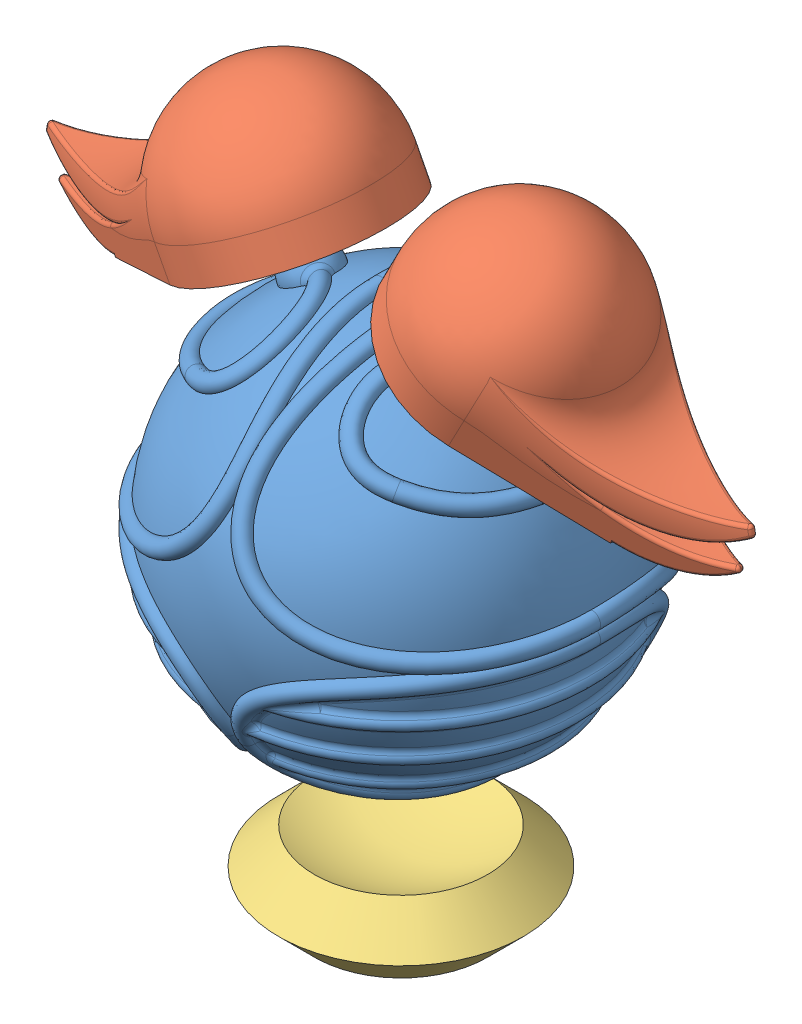
SolidWorks assembly Snitch Clock Assembly, configuration Default. Lengths in mm.
Overall size (324.28 292.79 177.31).
4 component instances, 3 part files, 6 mates.
Components (placement in the parent):
- Snitch Clock-2: Snitch Clock [Default] at (43.137 109.2453 141.7651) size (169.18 189.84 147.07)
- Snitch Bell-1: Snitch Bell [Default] at (-5.3979 195.4946 141.7651) x (0.884645 0.466266 0) z (0 0 1) size (146.75 58.57 177.29)
- Snitch Bell-2: Snitch Bell [Default] at (91.6719 195.4946 141.7651) x (-0.884645 0.466266 0) z (0 0 -1) size (146.75 58.57 177.29)
- Electromagnetic Base-1: Electromagnetic Base [Default] at (43.137 -32.1518 141.7651) x (0.986329 0 0.164788) z (-0.164788 0 0.986329) size (102.46 30 102.46)
Mates (geometry in assembly coordinates):
- Coincident1: coincident anti-aligned: plane of Snitch Clock-2 through (-13.2811 216.2873 141.7651) normal (-0.466266 0.884645 0); plane of snitch bell-1 through (-13.2811 216.2873 141.7651) normal (0.466266 -0.884645 0)
- Concentric1: concentric anti-aligned: cylinder of Snitch Clock-2 through (5.3695 180.9015 141.7651) axis (-0.466266 0.884645 0) radius 6; cylinder of Snitch Bell-1 through (-13.2811 216.2873 141.7651) axis (0.466266 -0.884645 0) radius 6
- Coincident2: coincident anti-aligned: plane of Snitch Clock-2 through (99.5552 216.2873 141.7651) normal (0.466266 0.884645 0); plane of snitch bell-2 through (99.5552 216.2873 141.7651) normal (-0.466266 -0.884645 0)
- Concentric2: concentric anti-aligned: cylinder of Snitch Clock-2 through (80.9045 180.9015 141.7651) axis (0.466266 0.884645 0) radius 6; cylinder of Snitch Bell-2 through (99.5552 216.2873 141.7651) axis (-0.466266 -0.884645 0) radius 6
- Coincident3: coincident anti-aligned: line of Snitch Clock-2 through (43.137 108.9582 141.7651) axis (0 -1 0); line of Electromagnetic Base-1 through (43.137 -27.0548 141.7651) axis (0 1 0)
- Distance4: distance = 40 mm aligned: sphere of Electromagnetic Base-1; sphere of Snitch Clock-2
